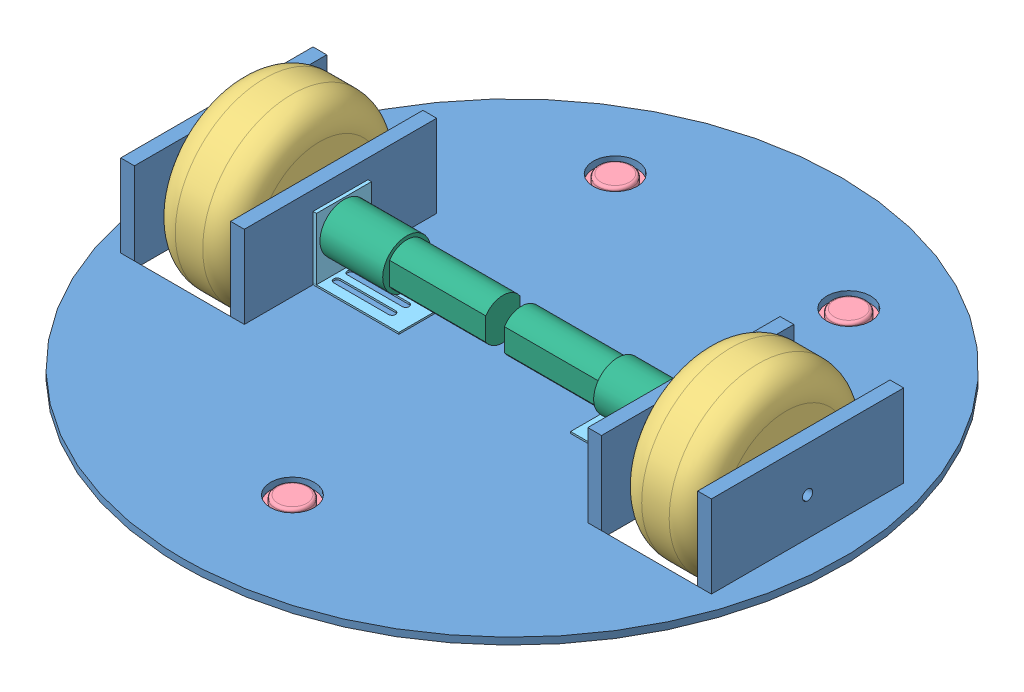
SolidWorks assembly Drive_train, configuration Default. Lengths in mm.
Overall size (304.8 103.88 304.8).
14 component instances, 6 part files, 14 mates.
Components (placement in the parent):
- Frame-1: Frame [Default] at (-42.0804 -19.5071 17.1232) size (304.8 41.27 304.8)
- Extended shaft-1: Extended shaft [Default] at (-172.2427 1.1304 17.1232) size (39.67 4.76 4.76)
- Extended shaft-2: Extended shaft [Default] at (48.4071 1.1304 17.1232) size (39.67 4.76 4.76)
- Wheel-1: Wheel [Default] at (-169.2503 1.1304 17.1232) x (1 0 0) z (0 0.983357 0.181685) size (38.1 82.55 82.55)
- Wheel-2: Wheel [Default] at (46.3586 1.1304 17.1232) x (1 0 0) z (0 -0.30644 0.95189) size (38.1 82.55 82.55)
- Ball_bearing-1: Ball_bearing [Default] at (-42.0804 -21.0946 118.7232) size (28.57 23.81 28.57)
- Ball_bearing-2: Ball_bearing [Default] at (11.8946 -21.0946 -84.4768) size (28.57 23.81 28.57)
- Ball_bearing-3: Ball_bearing [Default] at (-96.0554 -21.0946 -84.4768) size (28.57 23.81 28.57)
- Motor-4: Motor [Default] at (-112.1228 -14.6164 24.7935) x (-1 0 0) z (0 0 -1) size (86.18 30.16 25.4)
  - Bracket_motor-1: Bracket_motor [Default] at (-11.3048 -2.5094 7.6703) size (39.69 30.16 25.4)
  - Motor-1: Motor [Default] at (7.7452 15.7468 7.6703) x (-1 0 0) z (0 0 -1) size (86.18 22.23 22.23)
- Motor-5: Motor [Default] at (27.9619 -14.6164 9.4529) size (86.18 30.16 25.4)
  - Bracket_motor-1: Bracket_motor [Default] at (-11.3048 -2.5094 7.6703) size (39.69 30.16 25.4)
  - Motor-1: Motor [Default] at (7.7452 15.7468 7.6703) x (-1 0 0) z (0 0 -1) size (86.18 22.23 22.23)
Mates (geometry in assembly coordinates):
- Concentric5: concentric anti-aligned: cylinder of Extended shaft-1 through (-132.5679 1.1304 17.1232) axis (-1 0 0) radius 2.3813; cylinder of Wheel-1 through (-169.2503 1.1304 17.1232) axis (1 0 0) radius 2.3813
- Concentric6: concentric anti-aligned: cylinder of Extended shaft-2 through (88.0819 1.1304 17.1232) axis (-1 0 0) radius 2.3813; cylinder of Wheel-2 through (46.3586 1.1304 17.1232) axis (1 0 0) radius 2.3813
- Coincident7: coincident anti-aligned: plane of Frame-1 through (-42.0804 -19.5071 17.1232) normal (0 -1 0); plane of Ball_bearing-1 through (-27.7929 -19.5071 104.4357) normal (0 1 0)
- Concentric7: concentric anti-aligned: cylinder of Frame-1 through (-42.0804 -19.5071 118.7232) axis (0 1 0) radius 10.16; cylinder of Ball_bearing-1 through (-42.0804 -16.3321 118.7232) axis (0 -1 0) radius 7.9375
- Coincident8: coincident anti-aligned: plane of Frame-1 through (-42.0804 -19.5071 17.1232) normal (0 -1 0); plane of Ball_bearing-2 through (26.1821 -19.5071 -98.7643) normal (0 1 0)
- Coincident9: coincident anti-aligned: plane of Frame-1 through (-42.0804 -19.5071 17.1232) normal (0 -1 0); plane of Ball_bearing-3 through (-81.7679 -19.5071 -98.7643) normal (0 1 0)
- Concentric8: concentric anti-aligned: cylinder of Frame-1 through (-96.0554 -19.5071 -84.4768) axis (0 1 0) radius 10.16; cylinder of Ball_bearing-3 through (-96.0554 -16.3321 -84.4768) axis (0 -1 0) radius 7.9375
- Concentric9: concentric anti-aligned: cylinder of Frame-1 through (11.8946 -19.5071 -84.4768) axis (0 1 0) radius 10.16; cylinder of Ball_bearing-2 through (11.8946 -16.3321 -84.4768) axis (0 -1 0) radius 7.9375
- Coincident12: coincident anti-aligned: plane of Frame-1 through (-121.4554 21.7679 -27.3268) normal (1 0 0); plane of Motor-4/Bracket_motor-1 through (-121.4554 -15.5384 29.8232) normal (-1 0 0)
- Concentric12: concentric aligned: cylinder of Frame-1 through (-194.4804 1.1304 17.1232) axis (1 0 0) radius 2.3813; cylinder of Motor-4/Motor-1 through (-132.5679 1.1304 17.1232) axis (1 0 0) radius 2.3813
- Parallel1: parallel aligned: line of Frame-1 through (-121.4554 21.7679 61.5732) axis (0 0 -1); line of Motor-4/Bracket_motor-1 through (-119.8679 13.0366 29.8232) axis (0 0 -1)
- Concentric13: concentric: cylinder of Frame-1 through (-194.4804 1.1304 17.1232) axis (1 0 0) radius 2.3813; cylinder of Motor-5/Motor-1 through (4.3539 1.1304 17.1232) axis (-1 0 0) radius 2.3813
- Parallel2: parallel: line of Frame-1 through (37.2946 21.7679 61.5732) axis (0 0 -1); line of Motor-5/Bracket_motor-1 through (-6.7586 13.0366 4.4232) axis (0 0 1)
- Coincident16: coincident anti-aligned: plane of Frame-1 through (37.2946 21.7679 -27.3268) normal (-1 0 0); plane of Motor-5/Bracket_motor-1 through (37.2946 -15.5384 4.4232) normal (1 0 0)
